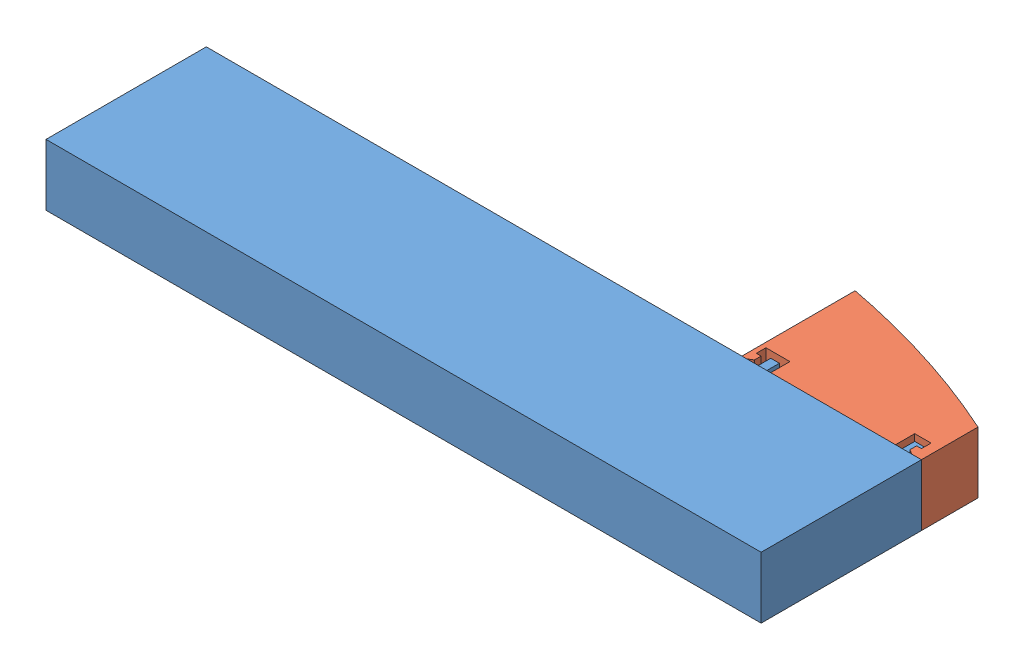
SolidWorks assembly Assem3, configuration Default. Lengths in mm.
Overall size (74.5 6.4 28.49).
2 component instances, 2 part files, 3 mates.
Components (placement in the parent):
- P11-1: P11 [Default] at origin size (74.5 6.4 18.7)
- Cap-P11-1: Cap-P11 [Default] at (-9.35 3.2 -18.7) x (1 0 0) z (0 1 0) size (18.7 11.79 6.4)
Mates (geometry in assembly coordinates):
- Concentric1: concentric: cylinder of P11-1 through (-5.1 4.45 -3.7) axis (0 0 -1) radius 1.05; cylinder of Cap-P11-1 through (-5.1 4.45 -35.4775) axis (0 0 1) radius 1.1
- Concentric2: concentric: cylinder of P11-1 through (-12.6 1.95 -3.7) axis (0 0 -1) radius 1.05; cylinder of Cap-P11-1 through (-12.6 1.95 -37.8775) axis (0 0 1) radius 1.1
- Coincident1: coincident anti-aligned: plane of P11-1 through (0 0 -18.7) normal (0 0 -1); plane of Cap-P11-1 through (-9.35 3.2 -18.7) normal (0 0 1)
